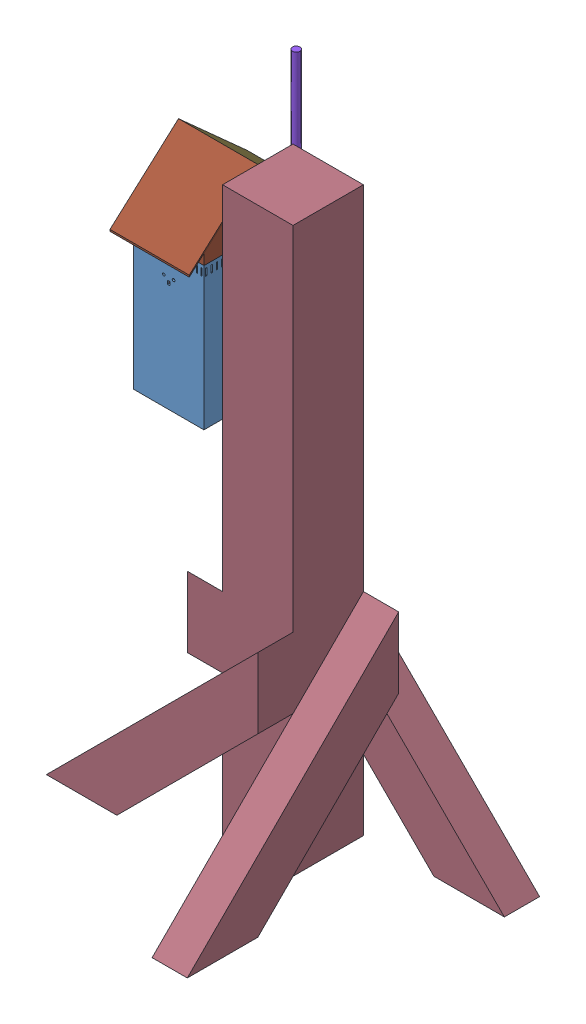
SolidWorks assembly House on post, configuration Default. Lengths in mm.
Overall size (508 876.3 508).
15 component instances, 14 part files, 4 mates.
Components (placement in the parent):
- Sensor Housing-1: Sensor Housing [Default] at (22.5116 55.2626 111.9766) size (114.3 359.73 217.88)
  - Base-1: Base [Default] at (135.2975 1.996 228.6908) size (101.6 205.74 152.4)
  - Door-1: Door [Default] at (48.6462 70.9281 105.6894) x (0 1 0) z (0 0 1) size (203.2 3.81 146.94)
  - Gecko-1: Gecko [Default] at (68.0476 0.4083 35.1436) size (2.5 25.4 2.5) (hidden)
  - PCB-1: PCB [Default] at (133.1252 77.7131 143.023) x (0 0 1) z (0 -1 0) size (90 50.8 170)
  - Light sensor-1: Light sensor [Default] at (93.1419 162.4188 223.6108) x (1 0 0) z (0 -1 0) size (19.05 1.4 16.51)
  - AC Plug-1: AC Plug [Default] at (118.9484 17.8288 73.2908) x (1 0 0) z (0 -1 0) size (28.3 15.5 16)
  - DC Plug-1: DC Plug [Default] at (92.2472 27.17 76.2908) x (-1 0 0) z (0 0 -1) size (57 57 19.5)
  - U.FL to SMA Bulkhead-1: U.FL to SMA Bulkhead [Default] at (95.0252 169.636 80.3308) x (0.636486 0.771288 0) z (0 0 -1) size (9 8 14)
  - Antenna-1: Antenna [Default] at (95.0252 169.636 76.2908) x (0 1 0) z (-1 0 0) size (196 37 11)
  - PCB washers-1: PCB washers [Default] at (133.1252 1.996 76.2908) x (0 0 -1) z (1 0 0) size (84.47 164.47 10.16)
  - Light sensor washers-1: Light sensor washers [Default] at (54.7528 1.996 224.8808) size (19.05 5.08 1.27)
  - Roof1-1: Roof1 [Default] at (124.8884 220.436 128.6716) x (0 0 1) z (-1 0 0) size (101.32 92.71 114.3)
  - Roof2-1: Roof2 [Default] at (124.8884 220.436 128.6716) x (0 0 1) z (-1 0 0) size (101.32 92.71 114.3)
- Stand-1: Stand [Default] at (228.1769 -460.9014 276.1434) size (508 812.8 508)
Mates (geometry in assembly coordinates):
- Coincident6: coincident: line of Sensor Housing-1/Roof1-1 through (170.2649 351.8986 264.9674) axis (-1 0 0); plane of Stand-1 through (228.1769 351.8986 289.2009) normal (0 1 0)
- Coincident7: coincident: plane of Sensor Housing-1/Roof2-1 through (170.2649 262.9986 166.1896) normal (1 0 0); plane of Stand-1 through (170.2649 351.8986 214.1674) normal (-1 0 0)
- Parallel2: parallel: line of Sensor Housing-1/Base-1 through (168.3368 57.2586 340.6674) axis (0 0 -1); line of Stand-1 through (170.2649 351.8986 214.1674) axis (0 0 1)
- Coincident9: coincident: point of Sensor Housing-1/Roof1-1; moEndPointRef_w of Stand-1
